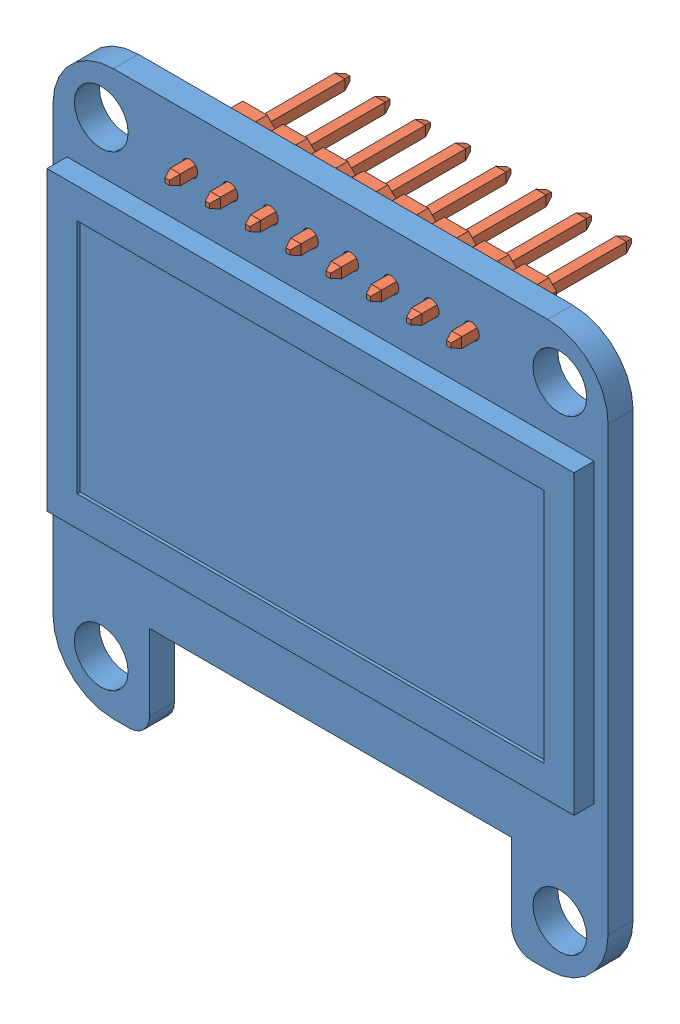
SolidWorks assembly oled, configuration Default. Lengths in mm.
Overall size (35.05 35.56 11.4).
9 component instances, 2 part files, 6 mates.
Components (placement in the parent):
- stemma  pcb-1: stemma  pcb [Default] at (-14.4442 -13.9876 35.56) size (35.05 35.56 2.84)
- 2.54mm_pin_header-1: 2.54mm_pin_header [Default] at (8.9223 15.4672 35.56) x (-1 0 0) z (0 0 -1) size (2.54 2.5 11.4)
- 2.54mm_pin_header-2: 2.54mm_pin_header [Default] at (6.398 15.4674 35.56) x (-1 0 0) z (0 0 -1) size (2.54 2.5 11.4)
- 2.54mm_pin_header-3: 2.54mm_pin_header [Default] at (3.857 15.4847 35.56) x (-1 0 0) z (0 0 -1) size (2.54 2.5 11.4)
- 2.54mm_pin_header-4: 2.54mm_pin_header [Default] at (1.3163 15.471 35.56) x (-1 0 0) z (0 0 -1) size (2.54 2.5 11.4)
- 2.54mm_pin_header-5: 2.54mm_pin_header [Default] at (-1.2269 15.4725 35.56) x (-1 0 0) z (0 0 -1) size (2.54 2.5 11.4)
- 2.54mm_pin_header-6: 2.54mm_pin_header [Default] at (-3.7746 15.4808 35.56) x (-1 0 0) z (0 0 -1) size (2.54 2.5 11.4)
- 2.54mm_pin_header-7: 2.54mm_pin_header [Default] at (-6.3119 15.4772 35.56) x (-1 0 0) z (0 0 -1) size (2.54 2.5 11.4)
- 2.54mm_pin_header-8: 2.54mm_pin_header [Default] at (-8.8515 15.4762 35.56) x (-1 0 0) z (0 0 -1) size (2.54 2.5 11.4)
Mates (geometry in assembly coordinates):
- Coincident1: coincident anti-aligned: plane of stemma  pcb-1 through (-14.4442 -13.9876 35.56) normal (0 0 -1); plane of 2.54mm_pin_header-1 through (8.9223 15.4672 35.56) normal (0 0 1)
- Parallel1: parallel aligned: plane of stemma  pcb-1 through (-17.4922 18.5244 37.1348) normal (0 1 0); plane of 2.54mm_pin_header-1 through (10.1923 16.7172 33.02) normal (0 1 0)
- Coincident2: coincident aligned: plane of 2.54mm_pin_header-3 through (3.857 15.4847 35.56) normal (0 0 1); plane of 2.54mm_pin_header-2 through (6.398 15.4674 35.56) normal (0 0 1)
- Coincident4: coincident anti-aligned: line of 2.54mm_pin_header-5 through (-1.5469 15.7925 35.56) axis (1 0 0); plane of 2.54mm_pin_header-4 through (1.3163 15.471 35.56) normal (0 0 1)
- Coincident6: coincident anti-aligned: plane of stemma  pcb-1 through (-14.4442 -13.9876 35.56) normal (0 0 -1); plane of 2.54mm_pin_header-6 through (-3.7746 15.4808 35.56) normal (0 0 1)
- Coincident7: coincident anti-aligned: plane of stemma  pcb-1 through (-14.4442 -13.9876 35.56) normal (0 0 -1); plane of 2.54mm_pin_header-8 through (-8.8515 15.4762 35.56) normal (0 0 1)
